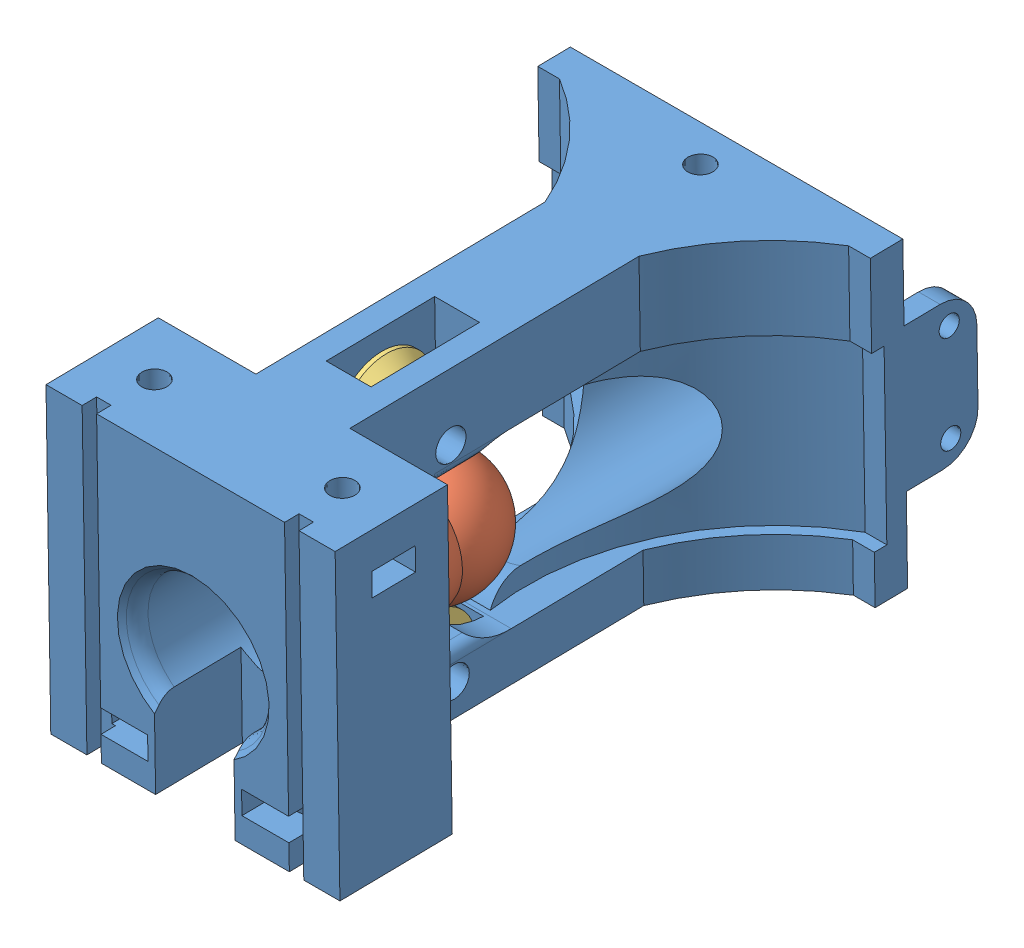
SolidWorks assembly 预置模组, configuration 默认. Lengths in mm.
Overall size (46 45.18 86.19).
5 component instances, 3 part files, 11 mates.
Components (placement in the parent):
- 枪管、-2: 枪管、 [默认] at (-7.3888 21.9699 -0.0454) x (1 0 0) z (0 -0.015696 0.999877) size (46 42 85.54)
- 17MM小弹丸-1: 17MM小弹丸 [默认] at (-7.3888 21.705 16.8251) x (0.00512 0.121757 -0.992547) z (0.861593 -0.504341 -0.057424) size (17 17 17)
- 槽轮4x13x6-1: 槽轮4x13x6 [默认] at (-7.3888 36.0535 13.8478) x (0 0 1) z (-1 0 0) size (13 13 6)
- 槽轮4x13x6-2: 槽轮4x13x6 [默认] at (-7.3888 7.457 13.3989) x (0 0 1) z (-1 0 0) size (13 13 6)
- 17MM小弹丸-2: 17MM小弹丸 [默认] at (-7.3888 21.8055 10.4216) x (0.906419 0.372277 0.199536) z (-0.139608 -0.1818 0.973375) size (17 17 17)
Mates (geometry in assembly coordinates):
- 同心6: concentric anti-aligned: cylinder of 枪管、-2 through (12.6112 36.0535 13.8478) axis (-1 0 0) radius 2.1; cylinder of 槽轮4x13x6-1 through (-7.3888 36.0535 13.8478) axis (1 0 0) radius 2
- 同心7: concentric anti-aligned: cylinder of 枪管、-2 through (12.6112 7.457 13.3989) axis (-1 0 0) radius 2.1; cylinder of 槽轮4x13x6-2 through (-7.3888 7.457 13.3989) axis (1 0 0) radius 2
- 宽度3: width anti-aligned: plane of 槽轮4x13x6-1 through (-10.3888 38.0535 13.8478) normal (-1 0 0); plane of 槽轮4x13x6-1 through (-4.3888 38.0535 13.8478) normal (1 0 0); plane of 枪管、-2 through (-0.8888 -1.9589 27.0823) normal (1 0 0); plane of 枪管、-2 through (-13.8888 -1.331 -12.9127) normal (-1 0 0)
- 宽度4: width aligned: plane of 槽轮4x13x6-2 through (-10.3888 9.457 13.3989) normal (-1 0 0); plane of 槽轮4x13x6-2 through (-4.3888 9.457 13.3989) normal (1 0 0); plane of 枪管、-2 through (-13.8888 -1.331 -12.9127) normal (-1 0 0); plane of 枪管、-2 through (-0.8888 -1.9589 27.0823) normal (1 0 0)
- 相切1: tangent: sphere of 17MM小弹丸-1; circle of 槽轮4x13x6-1
- 相切2: tangent: sphere of 17MM小弹丸-1; circle of 槽轮4x13x6-1
- 相切3: tangent: sphere of 17MM小弹丸-1; circle of 槽轮4x13x6-2
- 相切4: tangent: sphere of 17MM小弹丸-1; circle of 槽轮4x13x6-2
- 相切5: tangent anti-aligned: sphere of 17MM小弹丸-2; circle of 槽轮4x13x6-1
- 相切6: tangent: circle of 槽轮4x13x6-1; sphere of 17MM小弹丸-2
- 相切7: tangent: circle of 槽轮4x13x6-2; sphere of 17MM小弹丸-2
